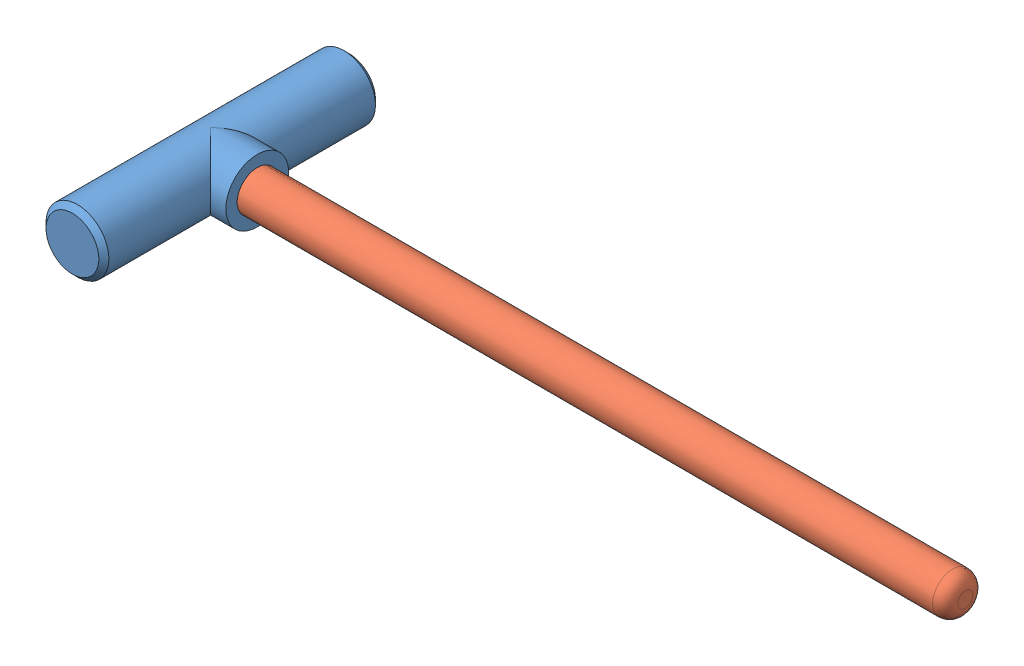
SolidWorks assembly Handle with shaft, configuration Default. Lengths in mm.
Overall size (312.5 25 110).
2 component instances, 2 part files, 2 mates.
Components (placement in the parent):
- Handle-3: Handle [Default<As Welded>] at (32.7874 88.3843 67.7523) size (31 25 110)
- Handle shaft-1: Handle shaft [Default] at (332.7874 88.3843 122.7523) x (0 0.585455 -0.810705) z (-1 0 0) size (16 18.48 300)
Mates (geometry in assembly coordinates):
- Concentric1: concentric: cylinder of Handle-3 through (32.7874 88.3843 122.7523) axis (1 0 0) radius 8; cylinder of Handle shaft-1 through (32.7874 88.3843 122.7523) axis (1 0 0) radius 8
- Coincident1: coincident: plane of Handle-3 through (32.7874 88.3843 122.7523) normal (1 0 0); plane of Handle shaft-1 through (32.7874 88.3843 122.7523) normal (-1 0 0)
